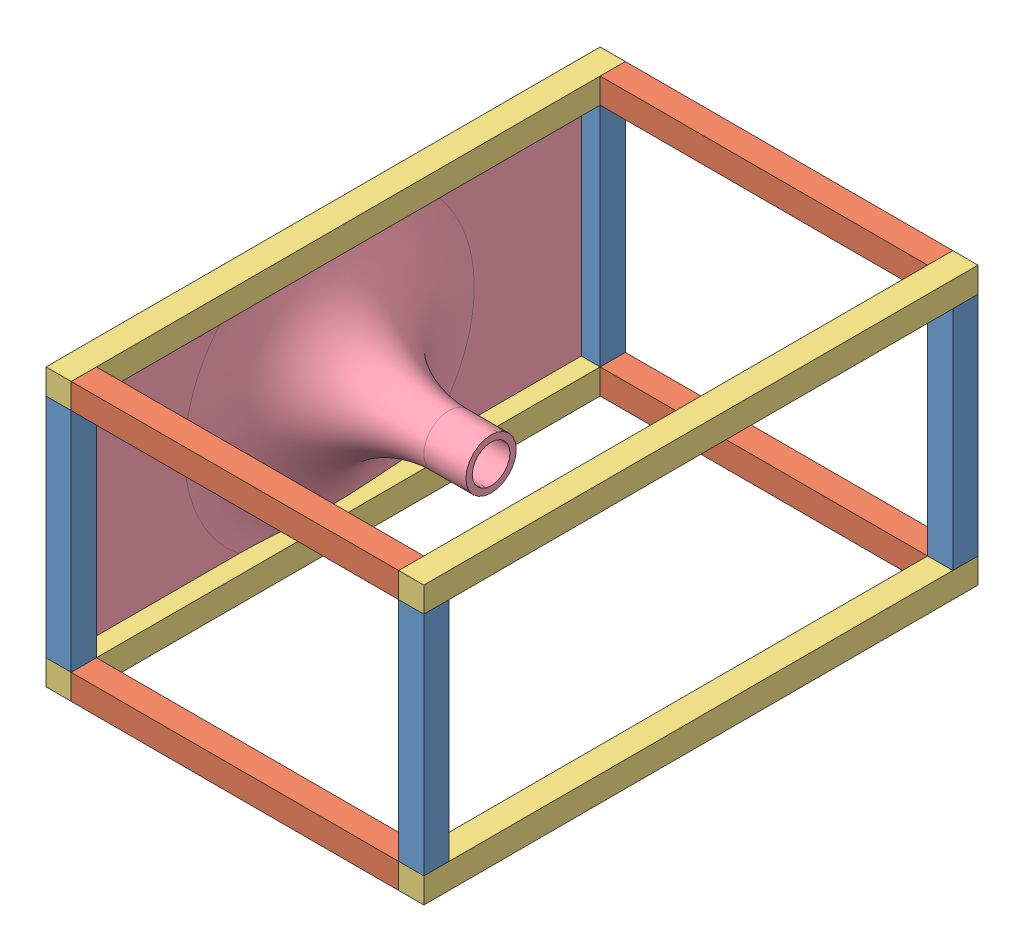
SolidWorks assembly Assemblage panier, configuration Défaut. Lengths in mm.
Overall size (303.18 220 440).
14 component instances, 5 part files, 35 mates.
Components (placement in the parent):
- Profilé 180mm 20x20-3: Profilé 180mm 20x20 [Défaut] at (23.2317 -26.1405 199.699) size (20 180 20)
- Profilé 260mm 20x20-3: Profilé 260mm 20x20 [Défaut] at (3.2317 -26.1405 199.699) x (0 1 0) z (0 0 1) size (20 260 20)
- Profilé 440mm 20x20-3: Profilé 440mm 20x20 [Défaut] at (23.2317 -26.1405 -240.301) x (0 1 0) z (1 0 0) size (20 440 20)
- Profilé 180mm 20x20-4: Profilé 180mm 20x20 [Défaut] at (23.2317 -26.1405 -220.301) size (20 180 20)
- Profilé 440mm 20x20-4: Profilé 440mm 20x20 [Défaut] at (23.2317 173.8595 199.699) x (1 0 0) z (0 1 0) size (20 440 20)
- Profilé 260mm 20x20-4: Profilé 260mm 20x20 [Défaut] at (3.2317 173.8595 199.699) x (0 1 0) z (0 0 1) size (20 260 20)
- Profilé 260mm 20x20-5: Profilé 260mm 20x20 [Défaut] at (3.2317 -26.1405 -220.301) x (0 1 0) z (0 0 1) size (20 260 20)
- Profilé 260mm 20x20-6: Profilé 260mm 20x20 [Défaut] at (3.2317 173.8595 -220.301) x (0 1 0) z (0 0 1) size (20 260 20)
- Pièce7^Assemblage panier-1: Pièce7^Assemblage panier [Défaut] at origin (virtual)
- Profilé 440mm 20x20-5: Profilé 440mm 20x20 [Défaut] at (-256.7683 -26.1405 -240.301) x (0 1 0) z (1 0 0) size (20 440 20)
- Profilé 440mm 20x20-6: Profilé 440mm 20x20 [Défaut] at (-256.7683 153.8595 -240.301) x (1 0 0) z (0 -1 0) size (20 440 20)
- Profilé 180mm 20x20-7: Profilé 180mm 20x20 [Défaut] at (-256.7683 -26.1405 -220.301) size (20 180 20)
- Profilé 180mm 20x20-8: Profilé 180mm 20x20 [Défaut] at (-256.7683 -26.1405 199.699) size (20 180 20)
- goulot-3: goulot [Défaut] at (-210.8799 50.63 -20.301) x (0 0 1) z (0 -1 0) size (400 136.58 180)
Mates (geometry in assembly coordinates):
- Coïncidente6: coincident anti-aligned: line of Profilé 180mm 20x20-3 through (3.2317 -26.1405 179.699) axis (0 0 1); line of Profilé 440mm 20x20-3 through (3.2317 -26.1405 199.699) axis (0 0 -1)
- Coïncidente7: coincident aligned: line of Profilé 180mm 20x20-3 through (23.2317 -26.1405 199.699) axis (0 0 -1); line of Profilé 440mm 20x20-3 through (23.2317 -26.1405 199.699) axis (0 0 -1)
- Coïncidente8: coincident anti-aligned: line of Profilé 180mm 20x20-3 through (3.2317 -26.1405 199.699) axis (1 0 0); line of Profilé 440mm 20x20-3 through (23.2317 -26.1405 199.699) axis (-1 0 0)
- Coïncidente10: coincident anti-aligned: line of Profilé 440mm 20x20-3 through (3.2317 -26.1405 199.699) axis (0 0 -1); line of Profilé 180mm 20x20-4 through (3.2317 -26.1405 -240.301) axis (0 0 1)
- Coïncidente11: coincident aligned: line of Profilé 440mm 20x20-3 through (23.2317 -26.1405 -240.301) axis (-1 0 0); line of Profilé 180mm 20x20-4 through (23.2317 -26.1405 -240.301) axis (-1 0 0)
- Coïncidente13: coincident anti-aligned: plane of Profilé 180mm 20x20-3 through (23.2317 153.8595 199.699) normal (0 1 0); plane of Profilé 440mm 20x20-4 through (23.2317 153.8595 -240.301) normal (0 -1 0)
- Coïncidente14: coincident anti-aligned: plane of Profilé 180mm 20x20-4 through (23.2317 153.8595 -220.301) normal (0 1 0); plane of Profilé 440mm 20x20-4 through (23.2317 153.8595 -240.301) normal (0 -1 0)
- Coïncidente15: coincident anti-aligned: line of Profilé 180mm 20x20-4 through (3.2317 153.8595 -240.301) axis (0 -1 0); line of Profilé 440mm 20x20-4 through (3.2317 153.8595 -240.301) axis (0 1 0)
- Coïncidente16: coincident anti-aligned: plane of Profilé 260mm 20x20-3 through (3.2317 -26.1405 199.699) normal (1 0 0); plane of Profilé 440mm 20x20-3 through (3.2317 -26.1405 199.699) normal (-1 0 0)
- Coïncidente17: coincident anti-aligned: line of Profilé 260mm 20x20-3 through (3.2317 -46.1405 199.699) axis (0 1 0); line of Profilé 440mm 20x20-3 through (3.2317 -26.1405 199.699) axis (0 -1 0)
- Coïncidente18: coincident anti-aligned: line of Profilé 260mm 20x20-3 through (3.2317 -46.1405 179.699) axis (0 0 1); line of Profilé 440mm 20x20-3 through (3.2317 -46.1405 199.699) axis (0 0 -1)
- Coïncidente19: coincident anti-aligned: plane of Profilé 440mm 20x20-4 through (3.2317 173.8595 -240.301) normal (-1 0 0); plane of Profilé 260mm 20x20-6 through (3.2317 173.8595 -220.301) normal (1 0 0)
- Coïncidente20: coincident anti-aligned: line of Profilé 440mm 20x20-4 through (3.2317 153.8595 -240.301) axis (0 1 0); line of Profilé 260mm 20x20-6 through (3.2317 173.8595 -240.301) axis (0 -1 0)
- Coïncidente21: coincident anti-aligned: line of Profilé 440mm 20x20-4 through (3.2317 173.8595 -240.301) axis (0 0 1); line of Profilé 260mm 20x20-6 through (3.2317 173.8595 -220.301) axis (0 0 -1)
- Coïncidente22: coincident anti-aligned: plane of Profilé 440mm 20x20-3 through (3.2317 -26.1405 199.699) normal (-1 0 0); plane of Profilé 260mm 20x20-5 through (3.2317 -26.1405 -220.301) normal (1 0 0)
- Coïncidente23: coincident anti-aligned: line of Profilé 440mm 20x20-3 through (3.2317 -46.1405 199.699) axis (0 0 -1); line of Profilé 260mm 20x20-5 through (3.2317 -46.1405 -240.301) axis (0 0 1)
- Coïncidente24: coincident: point of Profilé 440mm 20x20-3; line of Profilé 260mm 20x20-5 through (3.2317 -26.1405 -240.301) axis (0 -1 0)
- Coïncidente25: coincident anti-aligned: plane of Profilé 440mm 20x20-4 through (3.2317 173.8595 -240.301) normal (-1 0 0); plane of Profilé 260mm 20x20-4 through (3.2317 173.8595 199.699) normal (1 0 0)
- Coïncidente26: coincident aligned: line of Profilé 180mm 20x20-3 through (3.2317 153.8595 179.699) axis (0 0 1); line of Profilé 260mm 20x20-4 through (3.2317 153.8595 179.699) axis (0 0 1)
- Coïncidente27: coincident aligned: line of Profilé 440mm 20x20-4 through (3.2317 153.8595 199.699) axis (0 1 0); line of Profilé 260mm 20x20-4 through (3.2317 153.8595 199.699) axis (0 1 0)
- Coïncidente43: coincident anti-aligned: plane of Profilé 260mm 20x20-4 through (-256.7683 173.8595 199.699) normal (-1 0 0); plane of Profilé 440mm 20x20-6 through (-256.7683 153.8595 199.699) normal (1 0 0)
- Coïncidente44: coincident anti-aligned: line of Profilé 260mm 20x20-6 through (-256.7683 173.8595 -240.301) axis (0 -1 0); line of Profilé 440mm 20x20-6 through (-256.7683 153.8595 -240.301) axis (0 1 0)
- Coïncidente45: coincident aligned: line of Profilé 260mm 20x20-6 through (-256.7683 173.8595 -220.301) axis (0 0 -1); line of Profilé 440mm 20x20-6 through (-256.7683 173.8595 199.699) axis (0 0 -1)
- Coïncidente46: coincident anti-aligned: plane of Profilé 260mm 20x20-5 through (-256.7683 -26.1405 -220.301) normal (-1 0 0); plane of Profilé 440mm 20x20-5 through (-256.7683 -26.1405 199.699) normal (1 0 0)
- Coïncidente47: coincident anti-aligned: line of Profilé 260mm 20x20-5 through (-256.7683 -26.1405 -240.301) axis (0 -1 0); line of Profilé 440mm 20x20-5 through (-256.7683 -46.1405 -240.301) axis (0 1 0)
- Coïncidente48: coincident aligned: line of Profilé 260mm 20x20-5 through (-256.7683 -46.1405 -240.301) axis (1 0 0); line of Profilé 440mm 20x20-5 through (-276.7683 -46.1405 -240.301) axis (1 0 0)
- Coïncidente49: coincident anti-aligned: plane of Profilé 440mm 20x20-6 through (-256.7683 153.8595 199.699) normal (0 -1 0); plane of Profilé 180mm 20x20-8 through (-256.7683 153.8595 199.699) normal (0 1 0)
- Coïncidente50: coincident aligned: line of Profilé 440mm 20x20-6 through (-276.7683 153.8595 199.699) axis (1 0 0); line of Profilé 180mm 20x20-8 through (-276.7683 153.8595 199.699) axis (1 0 0)
- Coïncidente51: coincident anti-aligned: line of Profilé 440mm 20x20-6 through (-276.7683 153.8595 199.699) axis (0 0 -1); line of Profilé 180mm 20x20-8 through (-276.7683 153.8595 179.699) axis (0 0 1)
- Coïncidente52: coincident anti-aligned: plane of Profilé 440mm 20x20-6 through (-256.7683 153.8595 199.699) normal (0 -1 0); plane of Profilé 180mm 20x20-7 through (-256.7683 153.8595 -220.301) normal (0 1 0)
- Coïncidente53: coincident anti-aligned: line of Profilé 440mm 20x20-6 through (-276.7683 153.8595 199.699) axis (0 0 -1); line of Profilé 180mm 20x20-7 through (-276.7683 153.8595 -240.301) axis (0 0 1)
- Coïncidente54: coincident anti-aligned: line of Profilé 440mm 20x20-6 through (-276.7683 153.8595 -240.301) axis (1 0 0); line of Profilé 180mm 20x20-7 through (-256.7683 153.8595 -240.301) axis (-1 0 0)
- Coïncidente60: coincident: plane of Profilé 180mm 20x20-8 through (-256.7683 153.8595 179.699) normal (0 0 -1); plane of goulot-3 through (-271.7683 63.8595 179.699) normal (0 0 1)
- Coïncidente61: coincident: line of Profilé 180mm 20x20-8 through (-276.7683 153.8595 179.699) axis (0 -1 0); line of goulot-3 through (-276.7683 -26.1405 179.699) axis (0 1 0)
- Coïncidente62: coincident anti-aligned: line of Profilé 440mm 20x20-6 through (-276.7683 153.8595 199.699) axis (0 0 -1); line of goulot-3 through (-276.7683 153.8595 -220.301) axis (0 0 1)
